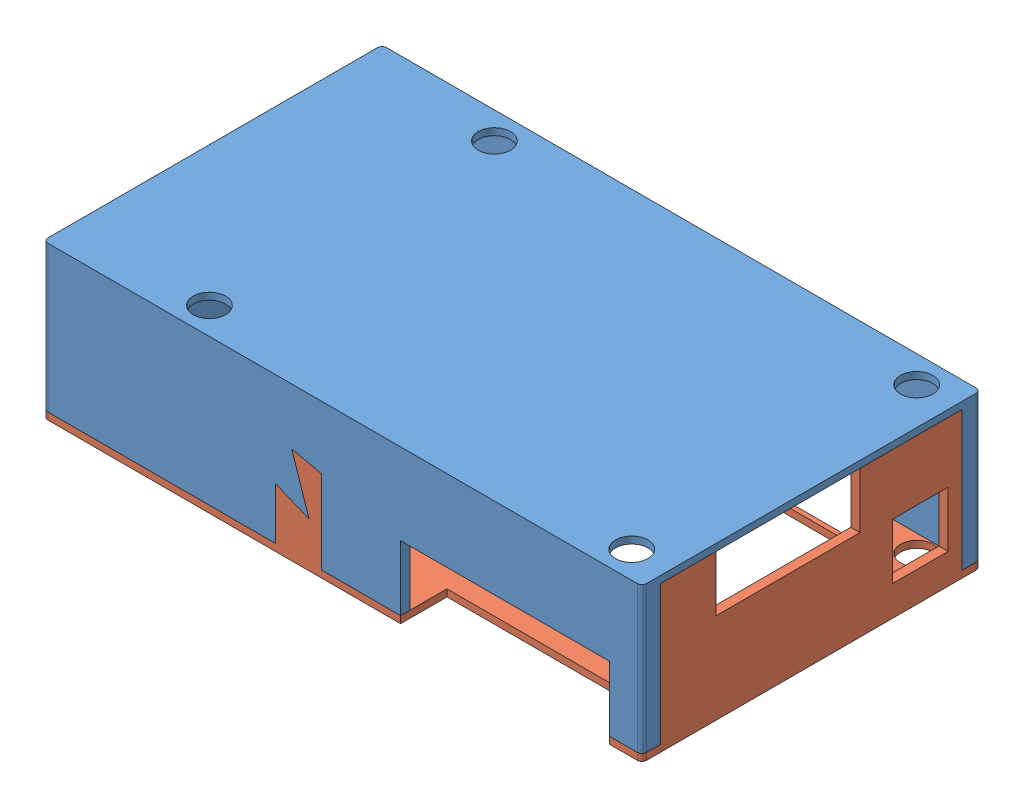
SolidWorks assembly bjut, configuration Default. Lengths in mm.
Overall size (129 33 73).
2 component instances, 2 part files, 3 mates.
Components (placement in the parent):
- bottom-1: bottom [默认] at (76.9768 97.5033 63.2059) size (129 31.5 73)
- up-1: up [默认] at (76.9768 67.5033 63.2059) x (-1 0 0) z (0 0 -1) size (129 31.5 73)
Mates (geometry in assembly coordinates):
- 重合7: coincident: plane of bottom-1 through (141.4768 99.0033 26.7059) normal (1 0 0); plane of up-1 through (141.4768 71.5272 63.2059) normal (1 0 0)
- 重合9: coincident: plane of bottom-1 through (12.4768 99.0033 26.7059) normal (0 0 -1); plane of up-1 through (141.4768 40.0272 26.7059) normal (0 0 -1)
- 重合10: coincident anti-aligned: line of bottom-1 through (141.4768 97.5033 30.7059) axis (0 0 1); line of up-1 through (141.4768 97.5033 95.7059) axis (0 0 -1)
